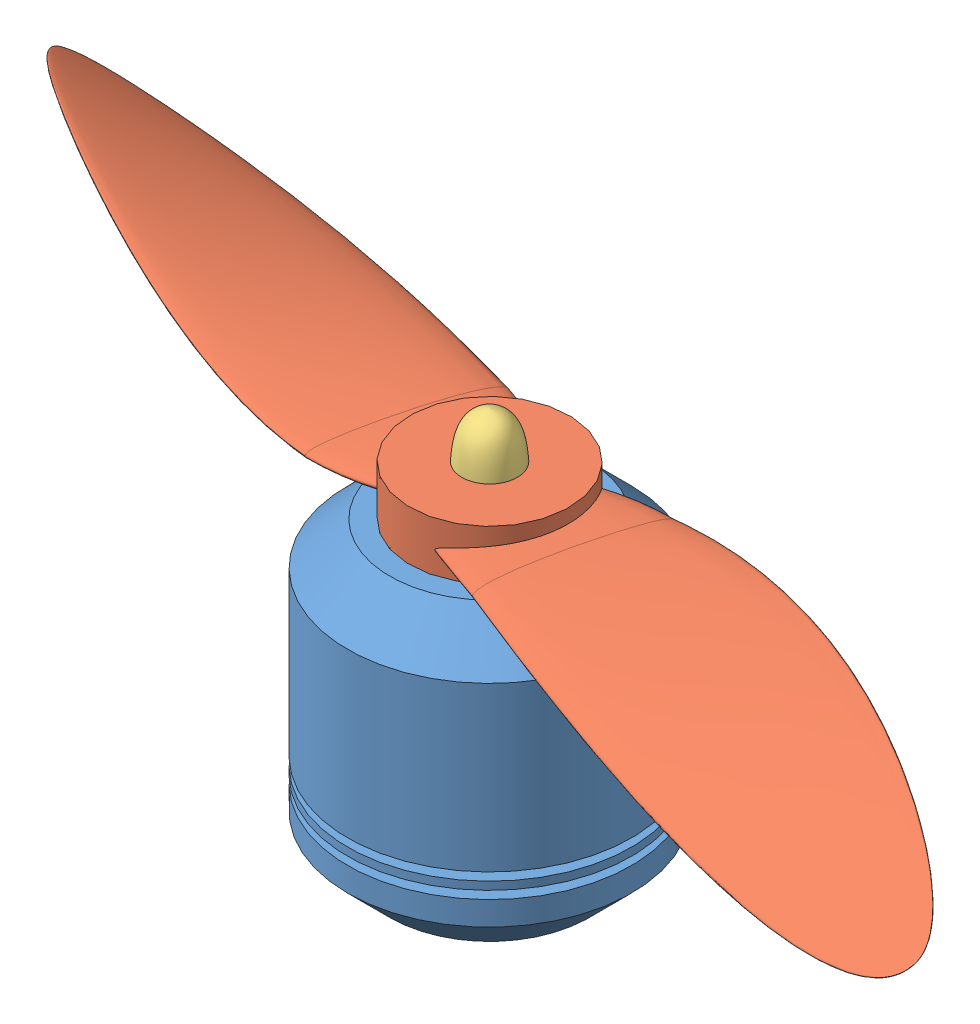
SolidWorks assembly Motor-Prop-Assembly, configuration Default. Lengths in mm.
Overall size (818.3 272.73 382.52).
3 component instances, 3 part files, 4 mates.
Components (placement in the parent):
- Drone_Motor-1: Drone_Motor [Default] at (71.1352 63.9264 193.4958) size (180.88 262.57 180.88)
- Drone_Propeller-1: Drone_Propeller [Default] at (48.4347 265.9003 186.5357) x (-0.290599 0.155574 0.944113) z (-0.955992 -0.005549 -0.293341) size (143.47 63.53 809.67)
- Drone_PropNut-1: Drone_PropNut [Default] at (71.1352 281.9822 193.4958) size (35.36 29.21 35.36)
Mates (geometry in assembly coordinates):
- Concentric1: concentric aligned: cylinder of Drone_Motor-1 through (71.1352 301.0322 193.4958) axis (0 -1 0) radius 12.7; cylinder of Drone_Propeller-1 through (71.1352 281.9822 193.4958) axis (0 -1 0) radius 12.7
- Coincident1: coincident anti-aligned: plane of Drone_Motor-1 through (134.6352 250.2322 193.4958) normal (0 1 0); plane of Drone_Propeller-1 through (71.1352 250.2322 193.4958) normal (0 -1 0)
- Concentric2: concentric aligned: cylinder of Drone_Motor-1 through (71.1352 301.0322 193.4958) axis (0 -1 0) radius 12.7; cylinder of Drone_PropNut-1 through (71.1352 301.0322 193.4958) axis (0 -1 0) radius 12.7
- Coincident2: coincident anti-aligned: plane of Drone_Propeller-1 through (71.1352 281.9822 193.4958) normal (0 1 0); plane of Drone_PropNut-1 through (83.8352 281.9822 193.4958) normal (0 -1 0)
